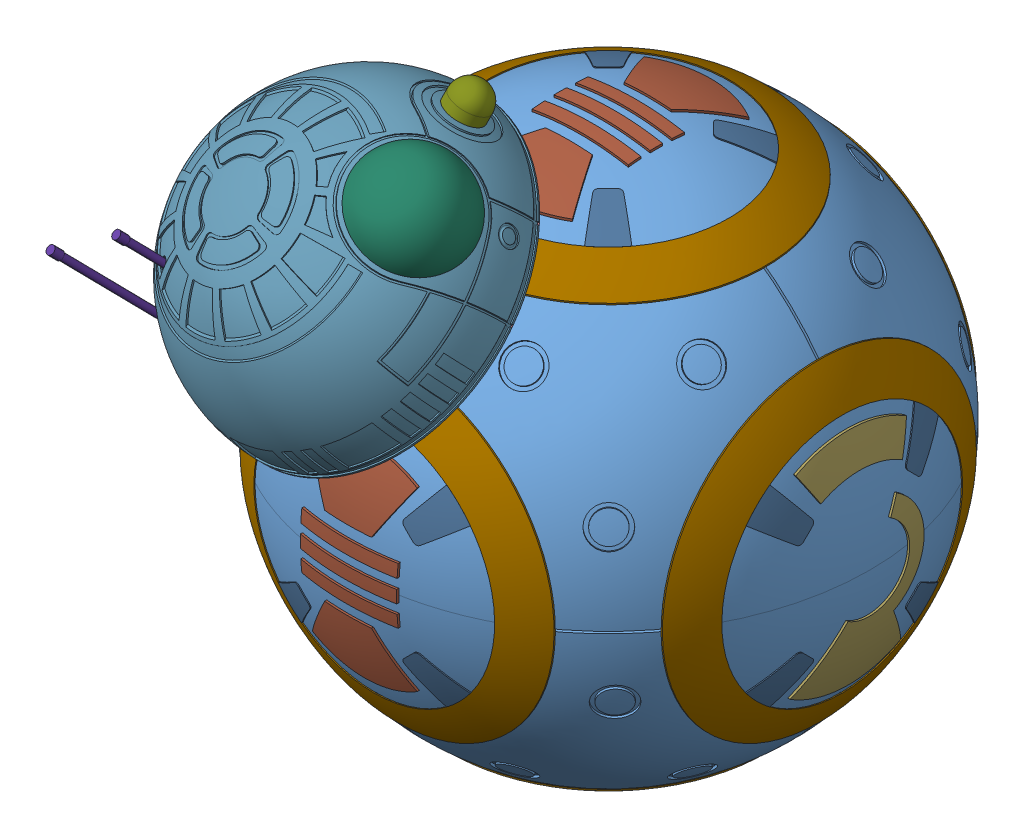
SolidWorks assembly 自动恢复 BB-8, configuration 默认. Lengths in mm.
Overall size (264.28 339.23 329.6).
69 component instances, 23 part files, 78 mates.
Components (placement in the parent):
- 外壳1-1: 外壳1 [默认] at origin size (250 125 250)
- 车轮-1: 车轮 [Default] at (-66.7454 -50.2728 0) x (0 0.963847 0.266455) z (-1 0 0) size (67 67 27.09)
- 减速电机2-1: 减速电机2 [Default] at (-78.2454 -61.7728 -0.85) x (0 0 -1) z (0 1 0) size (22.3 36.5 66)
- 零件2-1: 零件2 [默认] x (0 0 -1) z (1 0 0) size (203.46 53.08 91.5)
- 角球-1: 角球 [默认] at (0 -21.1972 98.799) x (1 0 0) z (0 -0.866025 -0.5) size (49 21 32)
- 角球-2: 角球 [默认] at (0 -21.1972 -98.799) x (1 0 0) z (0 0.866025 -0.5) size (49 21 32)
- 车轮-2: 车轮 [Default] at (66.7454 -50.2728 0) x (0 -0.963847 -0.266455) z (1 0 0) size (67 67 27.09)
- 减速电机2-2: 减速电机2 [Default] at (78.2454 -61.7728 0.85) x (0 0 1) z (0 1 0) size (22.3 36.5 66)
- 零件4-1: 零件4 [默认] at (0 -87.7728 0) x (1 0 0) z (0 1 0) size (130 130 3)
- 外壳1-2: 外壳1 [默认] x (1 0 0) z (0 0 -1) size (250 125 250)
- 支撑盘-1: 支撑盘 [默认] at (0 97.1173 0) x (-0.999887 0 -0.015054) z (0 1 0) size (90.75 90 26.01)
- 磁铁-1: 磁铁 [默认] at (-26.6869 105.5751 -0.4018) x (0.461532 0.134154 -0.876921) z (0.839529 0.253378 0.480615) size (30 10 30)
- 磁铁-2: 磁铁 [默认] at (26.6869 105.5751 0.4018) x (0.689502 -0.209444 0.69334) z (-0.665137 0.195783 0.720598) size (30 10 30)
- waike1-1: waike1 [默认] at origin size (150 150 11.53)
- waike2-1: waike2 [默认] at origin size (23.66 23.66 9.45)
- waike3-1: waike3 [默认] at origin size (50.06 98 10.99)
- waike4-1: waike4 [默认] x (0 0 -1) z (1 0 0) size (55.59 105.37 11.15)
- waike5-2: waike5 [默认] x (-0.039135 -0.440578 -0.896861) z (0.859814 -0.472145 0.19442) size (142.26 56.35 148) (hidden)
- waike6-2: waike6 [默认] at (-45.0417 -20.5801 -51.3764) x (0.977918 -0.079403 -0.193318) z (0.19393 0 0.981015) size (8.83 65.2 3.97) (hidden)
- waike5-3: waike5 [默认] x (0.121843 0 -0.992549) z (0.992549 0 0.121843) size (142.26 56.35 148) (hidden)
- waike71-1: waike71 [默认] at origin size (151.4 75.7 151.4) (hidden)
- waike71-2: waike71 [默认] x (0.848678 -0.522207 0.083938) z (0.14338 0.379906 0.913845) size (151.4 75.7 151.4) (hidden)
- waike6-3: waike6 [默认] at (-12.5703 -49.3558 -63.0912) x (-0.030051 -0.079403 0.99639) z (-0.999545 0 -0.030146) size (8.83 65.2 3.97) (hidden)
- waike1-2: waike1 [默认] x (0 0 -1) z (1 0 0) size (150 150 11.53)
- waike1-3: waike1 [默认] x (-1 0 0) z (0 0 -1) size (150 150 11.53)
- waike1-7: waike1 [默认] x (0 0 1) z (-1 0 0) size (150 150 11.53)
- waike1-5: waike1 [默认] x (-1 0 0) z (0 1 0) size (150 150 11.53)
- waike1-6: waike1 [默认] x (-1 0 0) z (0 -1 0) size (150 150 11.53)
- waike2-2: waike2 [默认] x (0 1 0) z (0 0 1) size (23.66 23.66 9.45)
- waike2-24: waike2 [默认] x (-1 0 0) z (0 0 1) size (23.66 23.66 9.45)
- waike2-30: waike2 [默认] x (0 -1 0) z (0 0 1) size (23.66 23.66 9.45)
- waike2-5: waike2 [默认] x (0 1 0) z (-1 0 0) size (23.66 23.66 9.45)
- waike2-6: waike2 [默认] x (0 1 0) z (0 0 -1) size (23.66 23.66 9.45)
- waike2-23: waike2 [默认] x (0 1 0) z (1 0 0) size (23.66 23.66 9.45)
- waike2-25: waike2 [默认] x (0 0 -1) z (-1 0 0) size (23.66 23.66 9.45)
- waike2-26: waike2 [默认] x (1 0 0) z (0 0 -1) size (23.66 23.66 9.45)
- waike2-29: waike2 [默认] x (0 0 1) z (1 0 0) size (23.66 23.66 9.45)
- waike2-31: waike2 [默认] x (0 -1 0) z (-1 0 0) size (23.66 23.66 9.45)
- waike2-32: waike2 [默认] x (0 -1 0) z (0 0 -1) size (23.66 23.66 9.45)
- waike2-35: waike2 [默认] x (0 -1 0) z (1 0 0) size (23.66 23.66 9.45)
- waike2-36: waike2 [默认] x (0 0 1) z (-1 0 0) size (23.66 23.66 9.45)
- waike2-37: waike2 [默认] x (-1 0 0) z (0 0 -1) size (23.66 23.66 9.45)
- waike2-40: waike2 [默认] x (0 0 -1) z (1 0 0) size (23.66 23.66 9.45)
- waike2-33: waike2 [默认] x (0 0 -1) z (0 1 0) size (23.66 23.66 9.45)
- waike2-34: waike2 [默认] x (0 0 1) z (0 -1 0) size (23.66 23.66 9.45)
- waike2-27: waike2 [默认] x (1 0 0) z (0 1 0) size (23.66 23.66 9.45)
- waike2-28: waike2 [默认] x (1 0 0) z (0 -1 0) size (23.66 23.66 9.45)
- waike2-21: waike2 [默认] x (0 0 1) z (0 1 0) size (23.66 23.66 9.45)
- waike2-22: waike2 [默认] x (0 0 -1) z (0 -1 0) size (23.66 23.66 9.45)
- waike2-38: waike2 [默认] x (-1 0 0) z (0 1 0) size (23.66 23.66 9.45)
- waike2-39: waike2 [默认] x (-1 0 0) z (0 -1 0) size (23.66 23.66 9.45)
- waike4-2: waike4 [默认] x (0 0 1) z (-1 0 0) size (55.59 105.37 11.15)
- waike3-2: waike3 [默认] x (1 0 0) z (0 -1 0) size (50.06 98 10.99)
- waike3-3: waike3 [默认] x (1 0 0) z (0 0 -1) size (50.06 98 10.99)
- waike3-4: waike3 [默认] x (1 0 0) z (0 1 0) size (50.06 98 10.99)
- 头部-5: 头部 [默认] x (0.99206 0 0.125767) z (-0.125767 0 0.99206) size (150 91.89 150) (hidden)
- 头部转盘-1: 头部转盘 [默认] at origin size (145 15.09 145) (hidden)
- 零件1^自动恢复 BB-8-1: 零件1^自动恢复 BB-8 [默认] at (-23.0712 217.9136 -91.6443) x (0.161969 -0.706027 0.689414) z (-0.787504 0.328521 0.521451) size (18.87 17.02 17.5) (hidden, virtual)
- datou-1: datou [默认] at origin size (145 75.5 145) (hidden)
- 眼睛-1: 眼睛 [默认] at (0 166.2584 51.0973) x (0.996538 0.023788 0.079662) z (-0.07948 -0.008485 0.9968) size (50 50 50) (hidden)
- 头部转盘-2: 头部转盘 [默认] x (0.695953 0.600017 -0.394499) z (0.685578 -0.391767 0.613597) size (145 15.09 145)
- datou-2: datou [默认] x (-0.480478 0.53462 -0.695214) z (0.850593 0.477161 -0.220927) size (145 75.5 145)
- 眼睛-2: 眼睛 [默认] at (7.9475 140.3459 102.4336) x (0.996538 0.023788 0.079662) z (-0.07948 -0.008485 0.9968) size (50 50 50)
- 零件1^自动恢复 BB-8-2: 零件1^自动恢复 BB-8 [默认] at (2.4506 -11.7511 9.9074) x (-0.237176 0.756342 0.609667) z (-0.894145 0.075399 -0.441384) size (18.87 17.02 17.5) (virtual)
- waike6-4: waike6 [默认] at (-30.9735 -71.7168 0.343) x (0.561325 0.608334 -0.56111) z (0.810035 -0.264926 0.523123) size (8.83 65.2 3.97)
- waike6-5: waike6 [默认] at (-43.3111 -74.6867 19.3759) x (0.561325 0.608334 -0.56111) z (0.810035 -0.264926 0.523123) size (8.83 65.2 3.97)
- SR403P舵机-1: SR403P舵机 [默认] at (-1.3 -31.3 0) x (1 0 0) z (0 1 0) size (54.4 21 41.65)
- 舵盘-2: 舵盘 [默认] at (26.6 0 0) x (0 0 1) z (-1 0 0) size (13 48.6 6)
- 脖子2-1: 脖子2 [默认] at origin size (59.55 112.12 30)
Mates (geometry in assembly coordinates):
- 在位1: in place: plane of ? through (0 0 0) normal (0 0 1); moOrthogonalPlaneRef_w of ? through (0 0 0) normal (0 1 0); plane of ? through (0 0 0) normal (1 0 0); unknown of ?
- 重合1: coincident aligned: plane of 外壳1-1; plane of assembly
- 重合2: coincident aligned: plane of ? through (0 0 0) normal (0 1 0)
- 重合3: coincident anti-aligned: plane of ? through (0 0 0) normal (1 0 0)
- 同心1: concentric anti-aligned: cylinder of 车轮-1 through (-64.7454 -50.2728 0) axis (-1 0 0) radius 7.5; cylinder of 减速电机2-1 through (-73.2454 -50.2728 0) axis (1 0 0) radius 2.75
- 重合4: coincident anti-aligned: plane of 车轮-1 through (-64.7454 -50.2728 0) normal (1 0 0); plane of 减速电机2-1 through (-64.7454 -50.2728 0) normal (-1 0 0)
- 平行2: parallel aligned: plane of 减速电机2-1 through (-45.7454 -24.7728 11.15) normal (1 0 0); plane of assembly through (0 0 0) normal (1 0 0)
- 对称1: symmetric aligned: plane of 减速电机2-1 through (-45.7454 -24.7728 11.15) normal (0 0 1); plane of 减速电机2-1 through (-45.7454 -24.7728 -11.15) normal (0 0 -1); plane of assembly through (0 0 0) normal (0 0 1)
- 相切2: tangent: sphere of 外壳1-1; torus of 车轮-1
- 在位2: in place: plane of ? through (0 0 0) normal (1 0 0); line of ? through (-55 0 0) axis (0 0 1); plane of ? through (0 0 0) normal (0 0 -1); unknown of ?
- 重合7: coincident aligned: plane of 零件2-1; plane of assembly
- 重合8: coincident aligned: line of ? through (-50.325 0 0) axis (0 0 1)
- 重合9: coincident anti-aligned: plane of ? through (0 0 0) normal (0 0 -1)
- 距离2: distance = 50 mm anti-aligned: plane of 零件4-1 through (0 -87.7728 0) normal (0 1 0); plane of 零件2-1 through (-45.75 -37.7728 100) normal (0 -1 0)
- 同心7: concentric anti-aligned: cylinder of 支撑盘-1 through (-18.0869 76.8345 -0.2723) axis (-0.286669 0.95802 -0.004316) radius 2; cylinder of 磁铁-1 through (-29.5536 115.1553 -0.445) axis (0.286669 -0.95802 0.004316) radius 3
- 重合29: coincident anti-aligned: plane of 支撑盘-1 through (-42.3678 100.9494 14.3638) normal (-0.286669 0.95802 -0.004316); plane of 磁铁-1 through (-26.6869 105.5751 -0.4018) normal (0.286669 -0.95802 0.004316)
- 同心8: concentric anti-aligned: cylinder of 支撑盘-1 through (18.0869 76.8345 0.2723) axis (0.286669 0.95802 0.004316) radius 2; cylinder of 磁铁-2 through (29.5536 115.1553 0.445) axis (-0.286669 -0.95802 -0.004316) radius 3
- 重合30: coincident anti-aligned: plane of 支撑盘-1 through (41.9162 100.9494 15.6328) normal (0.286669 0.95802 0.004316); plane of 磁铁-2 through (26.6869 105.5751 0.4018) normal (-0.286669 -0.95802 -0.004316)
- 在位6: in place: plane of ? through (0 0 0) normal (0 0 1); plane of ? through (0 0 0) normal (0 1 0); plane of ? through (0 0 0) normal (1 0 0); unknown of ?
- 重合31: coincident aligned: plane of 头部转盘-1; plane of assembly
- 重合32: coincident aligned: plane of ? through (0 0 0) normal (0 1 0)
- 重合33: coincident anti-aligned: plane of ? through (0 0 0) normal (1 0 0)
- 在位7: in place: plane of ? through (0 0 0) normal (0 0 1); plane of ? through (0 0 0) normal (0 1 0); plane of ? through (0 0 0) normal (1 0 0); unknown of ?
- 重合31: coincident aligned: plane of waike1-1; plane of assembly
- 重合32: coincident aligned: plane of ? through (0 0 0) normal (0 1 0)
- 重合33: coincident anti-aligned: plane of ? through (0 0 0) normal (1 0 0)
- 在位8: in place: plane of ? through (0 0 0) normal (0 0 1); plane of ? through (0 0 0) normal (0 1 0); plane of ? through (0 0 0) normal (1 0 0); unknown of ?
- 重合34: coincident aligned: plane of waike2-1; plane of assembly
- 重合35: coincident aligned: plane of ? through (0 0 0) normal (0 1 0)
- 重合36: coincident anti-aligned: plane of ? through (0 0 0) normal (1 0 0)
- 在位9: in place: plane of ? through (0 0 0) normal (0 0 1); plane of ? through (0 0 0) normal (0 1 0); plane of ? through (0 0 0) normal (1 0 0); unknown of ?
- 重合31: coincident aligned: plane of waike3-1; plane of assembly
- 重合32: coincident aligned: plane of ? through (0 0 0) normal (0 1 0)
- 重合33: coincident anti-aligned: plane of ? through (0 0 0) normal (1 0 0)
- 在位10: in place: plane of ? through (0 0 0) normal (1 0 0); line of ? through (-55 0 0) axis (0 0 1); plane of ? through (0 0 0) normal (0 0 -1); unknown of ?
- 重合34: coincident aligned: plane of waike4-1; plane of assembly
- 重合35: coincident aligned: line of ? through (-6.1298 0 0) axis (0 0 1)
- 重合36: coincident anti-aligned: plane of ? through (0 0 0) normal (0 0 -1)
- 同心16: concentric: sphere of 头部转盘-1; sphere of 头部-5
- 同心18: concentric: sphere of waike5-3; sphere of 头部-5
- 同心19: concentric aligned: circle of waike5-3; circle of 头部-5
- 在位13: in place: plane of ? through (0 0 0) normal (0 0 1); plane of ? through (0 0 0) normal (0 1 0); plane of ? through (0 0 0) normal (1 0 0); unknown of ?
- 重合39: coincident aligned: plane of waike71-1; plane of assembly
- 重合40: coincident aligned: plane of ? through (0 0 0) normal (0 1 0)
- 重合41: coincident anti-aligned: plane of ? through (0 0 0) normal (1 0 0)
- 在位15: in place: plane of ? through (0 0 0) normal (0 0 1); plane of ? through (0 0 0) normal (0 1 0); plane of ? through (0 0 0) normal (1 0 0); unknown of ?
- 重合32: coincident aligned: plane of datou-1; plane of assembly
- 重合33: coincident aligned: plane of ? through (0 0 0) normal (0 1 0)
- 重合34: coincident anti-aligned: plane of ? through (0 0 0) normal (1 0 0)
- 同心23: concentric aligned: cylinder of 零件1^自动恢复 BB-8-1 through (41.4608 148.7116 49.411) axis (-0.611327 -0.309017 -0.728552) radius 8.7475; cylinder of datou-1 through (0 127.7538 0) axis (-0.611327 -0.309017 -0.728552) radius 8.75
- 相切4: tangent aligned: sphere of 零件1^自动恢复 BB-8-1; sphere of datou-1
- 同心27: concentric: cylinder of datou-1 through (0 188.8585 81.0887) axis (0 -0.601815 -0.798636) radius 24.6443; sphere of 眼睛-1
- 相切6: tangent: circle of datou-1; sphere of 眼睛-1
- 同心28: concentric anti-aligned: cylinder of waike6-2 through (-22.165 243.0214 -55.8987) axis (0 1 0) radius 1.5895; cylinder of datou-1 through (-22.165 224 -55.8987) axis (0 -1 0) radius 2.25
- 相切7: tangent: sphere of waike6-2; curve of datou-1
- 同心29: concentric anti-aligned: cylinder of datou-1 through (-13.2733 224 -39.7824) axis (0 -1 0) radius 2.25; cylinder of waike6-3 through (-13.2733 214.2457 -39.7824) axis (0 1 0) radius 1.5895
- 同心30: concentric aligned: cylinder of 头部转盘-2 through (-35.7685 116.79 114.5321) axis (-0.213617 0.697495 0.68401) radius 70.5; cylinder of datou-2 through (-26.6495 87.0151 85.3328) axis (-0.213617 0.697495 0.68401) radius 72.5
- 重合31: coincident anti-aligned: plane of 头部转盘-2 through (23.8071 130.5163 56.7316) normal (-0.213617 0.697495 0.68401); plane of datou-2 through (-26.6495 87.0151 85.3328) normal (0.213617 -0.697495 -0.68401)
- 同心31: concentric: cylinder of datou-2 through (28.6302 170.4201 111.2664) axis (-0.550756 -0.80084 -0.235207) radius 24.6443; sphere of 眼睛-2
- 相切9: tangent: circle of datou-2; sphere of 眼睛-2
- 同心32: concentric aligned: cylinder of datou-2 through (-27.2903 89.1076 87.3848) axis (-0.259961 -0.890002 0.374589) radius 8.75; cylinder of 零件1^自动恢复 BB-8-2 through (-9.6596 149.4683 61.9799) axis (-0.259961 -0.890002 0.374589) radius 8.7475
- 相切10: tangent aligned: sphere of datou-2; sphere of 零件1^自动恢复 BB-8-2
- 同心34: concentric anti-aligned: cylinder of datou-2 through (-84.7474 117.7163 180.9771) axis (0.213617 -0.697495 -0.68401) radius 2.25; cylinder of waike6-5 through (-86.8864 124.7004 187.8262) axis (-0.213617 0.697495 0.68401) radius 1.5895
- 同心36: concentric anti-aligned: cylinder of datou-2 through (-75.3113 130.16 171.2349) axis (0.213617 -0.697495 -0.68401) radius 2.25; cylinder of waike6-4 through (-74.5488 127.6703 168.7934) axis (-0.213617 0.697495 0.68401) radius 1.5895
- 同心37: concentric: sphere of 外壳1-2; sphere of 头部转盘-2
- 距离5: distance = 100 mm anti-aligned: plane of waike6-5 through (-84.9084 118.242 181.4927) normal (-0.213617 0.697495 0.68401); plane of datou-2 through (-26.6495 87.0151 85.3328) normal (0.213617 -0.697495 -0.68401)
- 距离6: distance = 86.4174 mm anti-aligned: plane of waike6-4 through (-72.5708 121.212 162.4599) normal (-0.213617 0.697495 0.68401); plane of datou-2 through (-26.6495 87.0151 85.3328) normal (0.213617 -0.697495 -0.68401)
- 同心38: concentric aligned: cylinder of SR403P舵机-1 through (-102.0742 0 0) axis (1 0 0) radius 10.35
- 平行3: parallel anti-aligned: plane of 零件2-1 through (-45.75 -33.7728 100) normal (0 1 0); plane of SR403P舵机-1 through (-1.3 -31.3 0) normal (0 -1 0)
- 同心40: concentric anti-aligned: cylinder of 零件2-1 through (-19 -19.1972 95.3349) axis (0 -0.5 0.866025) radius 2; cylinder of 角球-1 through (-19 -21.7472 99.7516) axis (0 0.5 -0.866025) radius 2
- 同心41: concentric anti-aligned: cylinder of 零件2-1 through (19 -19.1972 95.3349) axis (0 -0.5 0.866025) radius 2; cylinder of 角球-1 through (19 -21.7472 99.7516) axis (0 0.5 -0.866025) radius 2
- 重合37: coincident anti-aligned: plane of 零件2-1 through (19.05 -24.1862 97.0733) normal (0 -0.5 0.866025); plane of 角球-1 through (0 -21.1972 98.799) normal (0 0.5 -0.866025)
- 同心42: concentric anti-aligned: cylinder of SR403P舵机-1 through (26.6 0 0) axis (-1 0 0) radius 3; cylinder of 舵盘-2 through (2.2963 0 0) axis (1 0 0) radius 4.35
- 重合38: coincident aligned: plane of SR403P舵机-1 through (26.6 0 0) normal (1 0 0); plane of 舵盘-2 through (26.6 21.8 0) normal (1 0 0)
- 在位16: in place: plane of ? through (0 0 0) normal (0 0 1); plane of ? through (0 0 0) normal (0 1 0); plane of ? through (0 0 0) normal (1 0 0); unknown of ?
- 重合39: coincident aligned: plane of 脖子2-1; plane of assembly
- 重合40: coincident aligned: plane of ? through (0 0 0) normal (0 1 0)
- 重合41: coincident anti-aligned: plane of ? through (0 0 0) normal (1 0 0)
